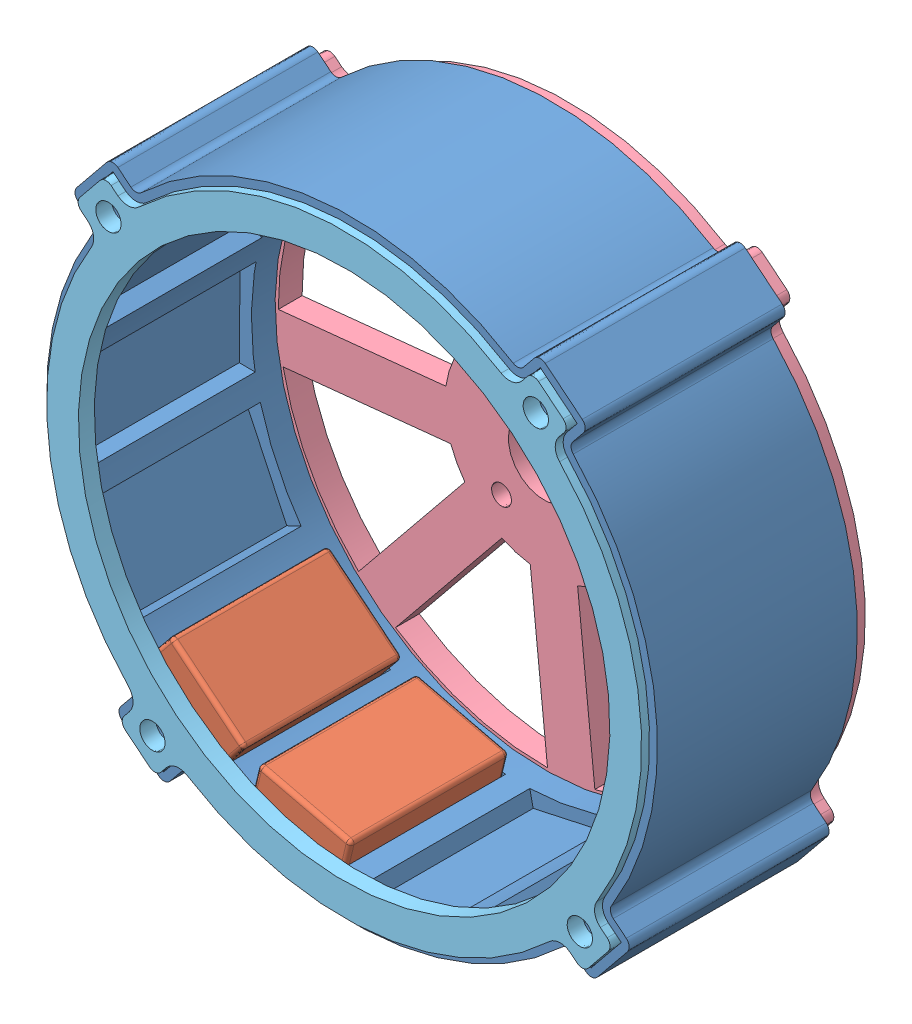
SolidWorks assembly brushless_1st, configuration ﾃﾞﾌｫﾙﾄ. Lengths in mm.
Overall size (118.99 118.99 38.2).
8 component instances, 5 part files, 18 mates.
Components (placement in the parent):
- outer-1: outer [ﾃﾞﾌｫﾙﾄ] at (3.288 -1.9247 42.8) x (-0.77582 0.630954 0) z (0 0 1) size (84.58 84.58 25.2)
- magnet-1: magnet [ﾃﾞﾌｫﾙﾄ] at (-15.9063 -25.4468 53) x (0 0 -1) z (-0.630954 -0.77582 0) size (20 12 5)
- magnet-2: magnet [ﾃﾞﾌｫﾙﾄ] at (22.4824 21.5974 53) x (0 0 1) z (0.630954 0.77582 0) size (20 12 5)
- magnet-3: magnet [ﾃﾞﾌｫﾙﾄ] at (-3.7024 -31.4687 53) x (0 0 1) z (-0.231855 -0.97275 0) size (20 12 5)
- SC_0810CKP4-1: SC_0810CKP4 [Default] at (3.288 -1.9247 26.8) x (0 0 1) z (0.99474 0.102435 0) size (10 24 24)
  - _SC__0810CKP4_2-1: _SC__0810CKP4_2 [Default] at origin size (10 24 24)
- plate-1: plate [ﾃﾞﾌｫﾙﾄ] at (3.288 -1.9247 39.8) x (0.77582 -0.630954 0) z (0 0 -1) size (82.58 82.58 3)
- plate_other-1: plate_other [ﾃﾞﾌｫﾙﾄ] at (3.288 -1.9247 65) x (0.630954 0.77582 0) z (0 0 -1) size (82.58 82.58 2)
Mates (geometry in assembly coordinates):
- 一致3: coincident: plane of outer-1 through (-14.3286 -33.1747 42.8) normal (0.630954 0.77582 0); plane of magnet-1 through (-19.0611 -29.3259 53) normal (-0.630954 -0.77582 0)
- 一致4: coincident: plane of outer-1 through (20.9046 29.3253 42.8) normal (-0.630954 -0.77582 0); plane of magnet-2 through (25.6371 25.4765 53) normal (0.630954 0.77582 0)
- 一致5: coincident: plane of outer-1 through (3.288 -1.9247 63) normal (0 0 1); plane of magnet-2 through (20.9822 29.2622 63) normal (0 0 1)
- 一致6: coincident: plane of outer-1 through (30.2921 21.6907 42.8) normal (-0.77582 0.630954 0); plane of magnet-2 through (30.2921 21.6907 43) normal (0.77582 -0.630954 0)
- 一致8: coincident: plane of outer-1 through (3.288 -1.9247 63) normal (0 0 1); plane of magnet-1 through (-23.716 -25.5401 63) normal (0 0 1)
- 一致9: coincident: plane of outer-1 through (-23.716 -25.5401 42.8) normal (0.77582 -0.630954 0); plane of magnet-1 through (-23.716 -25.5401 63) normal (-0.77582 0.630954 0)
- 一致10: coincident: plane of outer-1 through (0.9749 -37.7235 42.8) normal (0.231855 0.97275 0); plane of magnet-3 through (-4.8616 -36.3324 53) normal (-0.231855 -0.97275 0)
- 一致11: coincident: plane of outer-1 through (0.9749 -37.7235 42.8) normal (-0.97275 0.231855 0); plane of magnet-3 through (0.9749 -37.7235 43) normal (0.97275 -0.231855 0)
- 一致12: coincident: plane of outer-1 through (3.288 -1.9247 63) normal (0 0 1); plane of magnet-3 through (0.9749 -37.7235 63) normal (0 0 1)
- 相対固定1: in place: plane of ? through (3.288 -1.9247 39.8) normal (0 0 -1); plane of ? through (0 0 39.8) normal (0 0 -1); moOrthogonalPlaneRef_w of ? through (3.288 -1.9247 39.8) normal (0 0 -1); plane of ? through (0 0 39.8) normal (0 1 0); plane of ? through (3.288 -1.9247 39.8) normal (0 0 -1); plane of ? through (0 0 39.8) normal (-1 0 0); plane of outer-1 through (3.288 -1.9247 39.8) normal (0 0 -1); unknown of plate-1
- 一致22: coincident: plane of outer-1; plane of plate-1
- 一致23: coincident: moOrthogonalPlaneRef_w of outer-1; plane of plate-1 through (3.288 -1.9247 39.8) normal (-0.630954 -0.77582 0)
- 一致24: coincident: moOrthogonalPlaneRef_w of outer-1; plane of plate-1 through (3.288 -1.9247 39.8) normal (0.77582 -0.630954 0)
- 同心円9: concentric: cylinder of SC_0810CKP4-1/_SC__0810CKP4_2-1 through (9.8825 -7.2878 36.8) axis (0 0 1) radius 2.25; circle of plate-1
- 一致25: coincident: plane of SC_0810CKP4-1/_SC__0810CKP4_2-1 through (3.749 -6.401 36.8) normal (0 0 1); plane of plate-1 through (24.1312 31.6285 36.8) normal (0 0 -1)
- 一致26: coincident: plane of outer-1 through (3.288 -1.9247 63) normal (0 0 1); plane of plate_other-1 through (-30.2651 18.9184 63) normal (0 0 -1)
- 同心円10: concentric: circle of outer-1; circle of plate_other-1
- 同心円11: concentric: circle of outer-1; circle of plate_other-1
